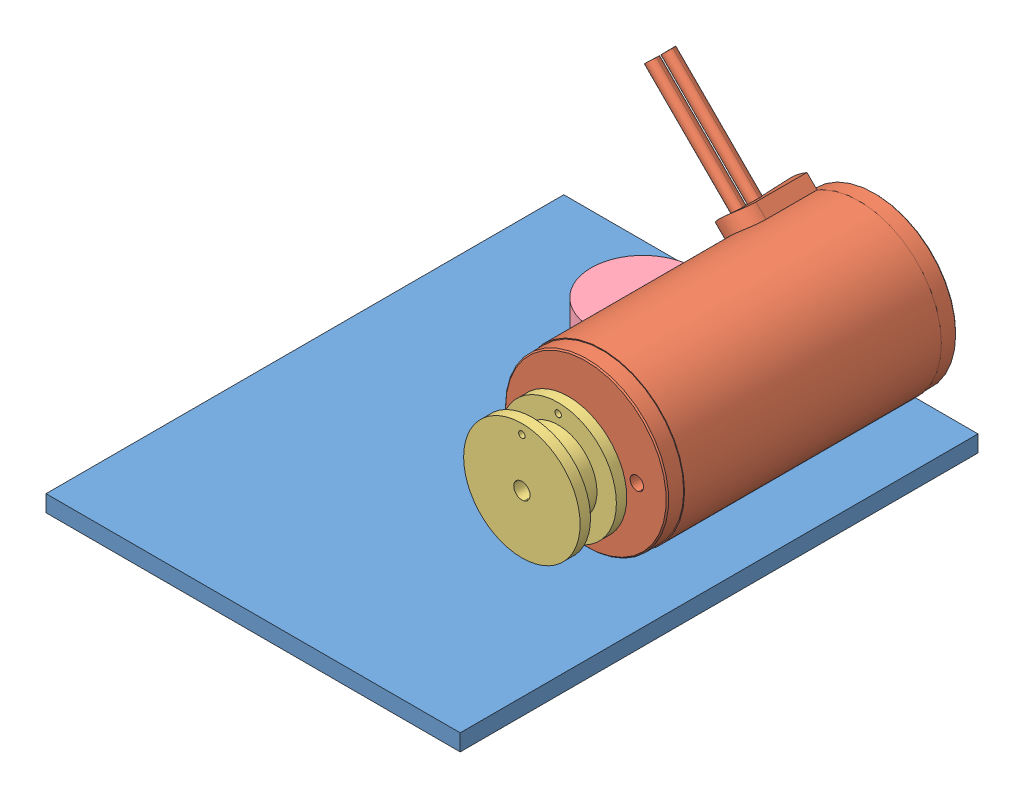
SolidWorks assembly levitation, configuration Default. Lengths in mm.
Overall size (101.6 63.17 127).
4 component instances, 4 part files, 5 mates.
Components (placement in the parent):
- base-1: base [Default] at origin size (101.6 4.06 127)
- bag motor-1: bag motor [Default] at (77.9232 24.264 -54.5) size (59.11 59.11 84.5)
- spool-2: spool [Default] at (77.9232 24.264 -47.69) size (28.57 28.57 11.43)
- steel cable weight anolog-1: steel cable weight anolog [Default] at (37.922 10.414 -108.4997) x (1 0 0) z (0 -1 0) size (25.4 25.4 6.35)
Mates (geometry in assembly coordinates):
- Coincident3: coincident anti-aligned: circle of bag motor-1; cylinder of spool-2 through (77.9232 24.264 -47.69) axis (0 0 1) radius 2
- Distance1: distance = 1.27 mm anti-aligned: plane of bag motor-1 through (77.9232 24.264 -51.5) normal (0 0 1); plane of spool-2 through (77.9232 24.264 -50.23) normal (0 0 -1)
- Coincident6: coincident aligned: plane of base-1 through (0 4.064 -127) normal (0 0 -1); plane of bag motor-1 through (77.9232 24.264 -127) normal (0 0 -1)
- Tangent1: tangent anti-aligned: plane of base-1 through (0 4.064 0) normal (0 1 0); cylinder of bag motor-1 through (77.9232 24.264 -125.5) axis (0 0 1) radius 20.2
- Coincident7: coincident anti-aligned: plane of base-1 through (0 4.064 0) normal (0 1 0); plane of steel cable weight anolog-1 through (37.922 4.064 -108.4997) normal (0 -1 0)
